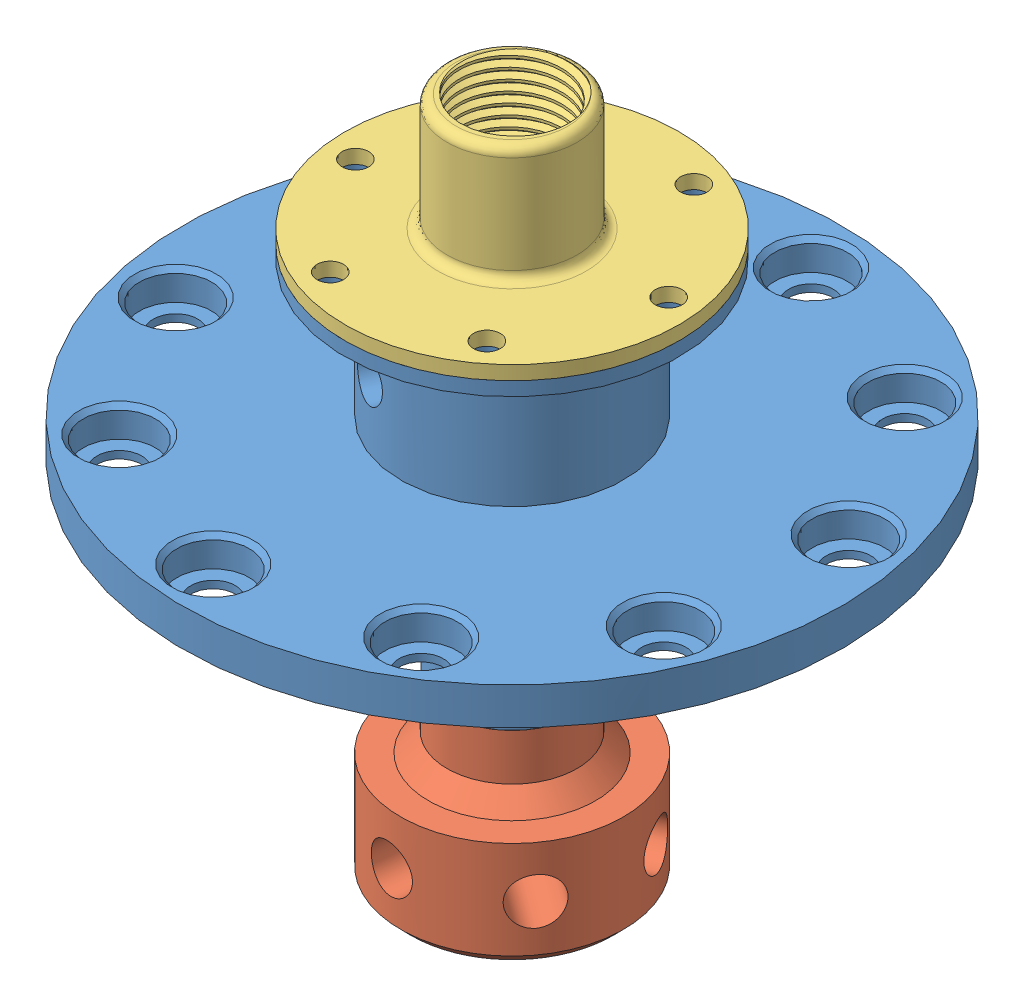
SolidWorks assembly 000012_R04_ASI_ASSEM, configuration Default. Lengths in mm.
Overall size (117.68 93.77 117.68).
3 component instances, 3 part files, 6 mates.
Components (placement in the parent):
- 000011-R02_ASI_TOP-1: 000011-R02_ASI_TOP [Default] at (0 37.9912 0) x (-0.924896 0 -0.380219) z (0.380219 0 -0.924896) size (90.17 60.14 90.17)
- 000011-R02_ASI_BOTTOM-1: 000011-R02_ASI_BOTTOM [Default] at (0 4.4632 0) x (0.915191 0 -0.40302) z (0.40302 0 0.915191) size (30.48 24.13 30.48)
- 000010-R02_ASI-1: 000010-R02_ASI [Default] at (0 63.3912 0) x (-0.133168 0 -0.991093) z (0.991093 0 -0.133168) size (45.72 18.88 45.72)
Mates (geometry in assembly coordinates):
- Concentric1: concentric anti-aligned: cylinder of 000011-R02_ASI_BOTTOM-1 through (0 4.4632 0) axis (0 -1 0) radius 8.89; line of assembly
- Concentric4: concentric aligned: cylinder of 000011-R02_ASI_TOP-1 through (0 63.3912 0) axis (0 1 0) radius 7.8092; line of assembly
- Concentric5: concentric aligned: circle of 000010-R02_ASI-1; line of assembly
- Coincident9: coincident anti-aligned: plane of 000011-R02_ASI_TOP-1 through (0 63.3912 0) normal (0 1 0); plane of 000010-R02_ASI-1 through (0 63.3912 0) normal (0 -1 0)
- Concentric6: concentric aligned: cylinder of 000011-R02_ASI_TOP-1 through (18.8803 4.4622 -2.5369) axis (0 1 0) radius 1.8288; cylinder of 000010-R02_ASI-1 through (18.8803 62.841 -2.5369) axis (0 1 0) radius 1.8288
- Coincident10: coincident anti-aligned: plane of 000011-R02_ASI_TOP-1 through (-5.8731 12.0832 -2.4144) normal (0 -1 0); plane of 000011-R02_ASI_BOTTOM-1 through (5.8115 12.0832 -2.5592) normal (0 1 0)
